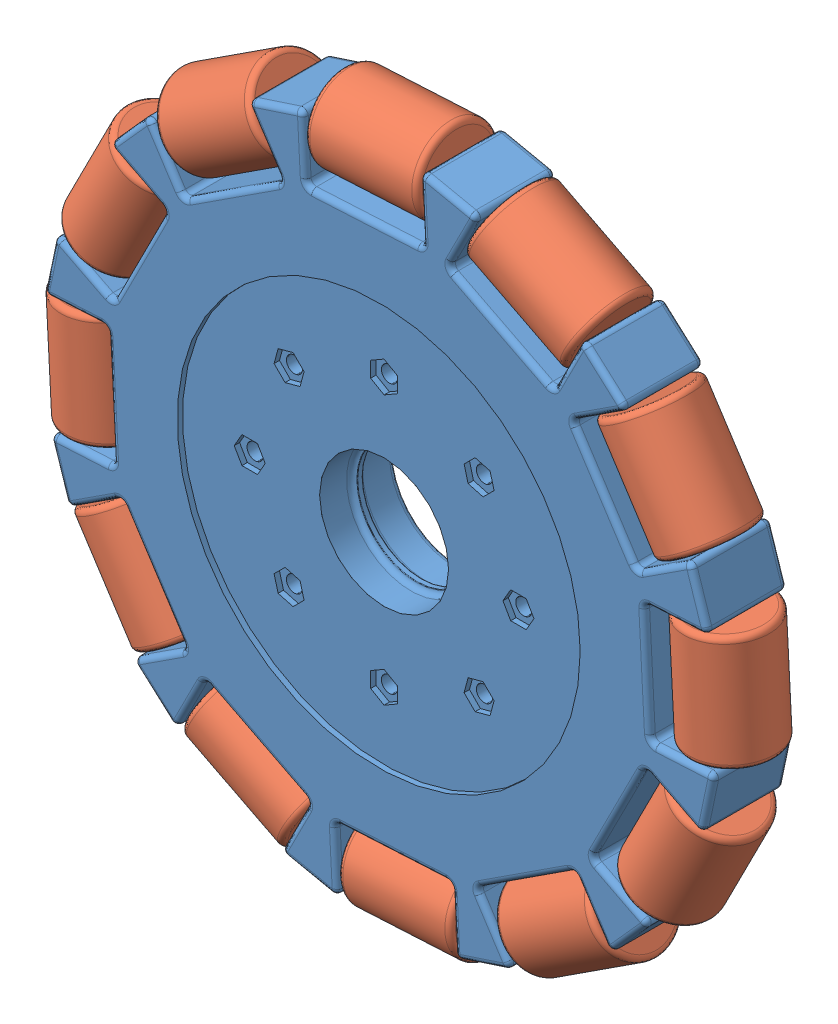
SolidWorks assembly single wheel assembly 1, configuration Default. Lengths in mm.
Overall size (138.11 135.78 21.9).
13 component instances, 2 part files, 24 mates.
Components (placement in the parent):
- basic-1: basic [Default] at (73.8485 -0.4973 -9.443) size (124.49 124.49 16)
- omni new-2: omni new [Default] at (131.2341 13.0674 -1.943) x (-0.527483 -0.02805 -0.849102) z (0.053103 -0.998589 0) size (15.5 15.5 21)
- omni new-3: omni new [Default] at (114.2887 -43.4123 -1.943) x (0.399732 -0.6145 -0.680151) z (-0.838252 -0.545283 0) size (15.5 15.5 21)
- omni new-4: omni new [Default] at (56.9031 -56.977 -1.943) x (0.429804 0.845142 0.31781) z (-0.891355 0.453306 0) size (15.5 15.5 21)
- omni new-5: omni new [Default] at (116.7635 39.9429 -1.943) x (-0.615632 -0.400469 0.678691) z (0.545283 -0.838252 0) size (15.5 15.5 21)
- omni new-6: omni new [Default] at (30.9334 -40.9374 -1.943) x (-0.31305 -0.203639 0.927648) z (-0.545283 0.838252 0) size (15.5 15.5 21)
- omni new-7: omni new [Default] at (130.3282 -17.4427 -1.943) x (0.582439 -0.296205 0.756986) z (-0.453306 -0.891355 0) size (15.5 15.5 21)
- omni new-8: omni new [Default] at (16.4629 -14.062 -1.943) x (0.884135 0.047016 -0.46486) z (-0.053103 0.998589 0) size (15.5 15.5 21)
- omni new-9: omni new [Default] at (87.4132 -57.8829 -1.943) x (-0.000877 0.016485 0.999864) z (-0.998589 -0.053103 0) size (15.5 15.5 21)
- omni new-10: omni new [Default] at (17.3687 16.4482 -1.943) x (-0.685244 0.348487 -0.639529) z (0.453306 0.891355 0) size (15.5 15.5 21)
- omni new-11: omni new [Default] at (60.2838 56.8883 -1.943) x (0.03476 -0.653654 0.755994) z (0.998589 0.053103 0) size (15.5 15.5 21)
- omni new-12: omni new [Default] at (33.4083 42.4178 -1.943) x (-0.043127 0.066299 0.996867) z (0.838252 0.545283 0) size (15.5 15.5 21)
- omni new-13: omni new [Default] at (90.7939 55.9825 -1.943) x (-0.379207 -0.745651 0.547911) z (0.891355 -0.453306 0) size (15.5 15.5 21)
Mates (geometry in assembly coordinates):
- Concentric1: concentric anti-aligned: cylinder of basic-1 through (52.3564 54.7435 -1.943) axis (-0.838252 -0.545283 0) radius 0.5; cylinder of omni new-12 through (7.674 25.6776 -1.943) axis (0.838252 0.545283 0) radius 0.505
- Concentric2: concentric anti-aligned: cylinder of basic-1 through (27.6154 36.5966 -1.943) axis (-0.453306 -0.891355 0) radius 0.5; cylinder of omni new-10 through (3.4522 -10.9164 -1.943) axis (0.453306 0.891355 0) radius 0.505
- Concentric4: concentric anti-aligned: cylinder of basic-1 through (15.2625 8.5104 -1.943) axis (0.053103 -0.998589 0) radius 0.5; cylinder of omni new-8 through (18.0931 -44.7187 -1.943) axis (-0.053103 0.998589 0) radius 0.505
- Concentric5: concentric anti-aligned: cylinder of basic-1 through (82.8562 58.0887 -1.943) axis (-0.998589 -0.053103 0) radius 0.5; cylinder of omni new-11 through (29.6271 55.2581 -1.943) axis (0.998589 0.053103 0) radius 0.505
- Concentric6: concentric anti-aligned: cylinder of basic-1 through (18.6077 -21.9893 -1.943) axis (0.545283 -0.838252 0) radius 0.5; cylinder of omni new-6 through (47.6736 -66.6718 -1.943) axis (-0.545283 0.838252 0) radius 0.505
- Concentric7: concentric anti-aligned: cylinder of basic-1 through (36.7546 -46.7303 -1.943) axis (0.891355 -0.453306 0) radius 0.5; cylinder of omni new-4 through (84.2676 -70.8935 -1.943) axis (-0.891355 0.453306 0) radius 0.505
- Concentric8: concentric anti-aligned: cylinder of basic-1 through (64.8408 -59.0832 -1.943) axis (0.998589 0.053103 0) radius 0.5; cylinder of omni new-9 through (118.0699 -56.2526 -1.943) axis (-0.998589 -0.053103 0) radius 0.505
- Concentric9: concentric anti-aligned: cylinder of basic-1 through (95.3406 -55.738 -1.943) axis (0.838252 0.545283 0) radius 0.5; cylinder of omni new-3 through (140.023 -26.6721 -1.943) axis (-0.838252 -0.545283 0) radius 0.505
- Concentric10: concentric anti-aligned: cylinder of basic-1 through (120.0816 -37.5912 -1.943) axis (0.453306 0.891355 0) radius 0.5; cylinder of omni new-7 through (144.2447 9.9219 -1.943) axis (-0.453306 -0.891355 0) radius 0.505
- Concentric11: concentric anti-aligned: cylinder of basic-1 through (132.4344 -9.505 -1.943) axis (-0.053103 0.998589 0) radius 0.5; cylinder of omni new-2 through (129.6038 43.7241 -1.943) axis (0.053103 -0.998589 0) radius 0.505
- Concentric12: concentric anti-aligned: cylinder of basic-1 through (129.0893 20.9948 -1.943) axis (-0.545283 0.838252 0) radius 0.5; cylinder of omni new-5 through (100.0233 65.6773 -1.943) axis (0.545283 -0.838252 0) radius 0.505
- Concentric13: concentric anti-aligned: cylinder of omni new-13 through (63.4293 69.899 -1.943) axis (0.891355 -0.453306 0) radius 0.505; cylinder of basic-1 through (110.9424 45.7358 -1.943) axis (-0.891355 0.453306 0) radius 0.5
- Width1: width anti-aligned: plane of omni new-12 through (51.0116 53.8687 -1.943) normal (0.838252 0.545283 0); plane of basic-1 through (33.4083 42.4178 -1.943) normal (-0.838252 -0.545283 0); plane of omni new-12 through (55.1739 48.1958 5.557) normal (-0.838252 -0.545283 0); plane of basic-1 through (36.9072 36.3133 5.557) normal (0.838252 0.545283 0)
- Width2: width anti-aligned: plane of omni new-10 through (26.8882 35.1666 -1.943) normal (0.453306 0.891355 0); plane of basic-1 through (17.3687 16.4482 -1.943) normal (-0.453306 -0.891355 0); plane of omni new-10 through (33.3293 32.3349 5.557) normal (-0.453306 -0.891355 0); plane of basic-1 through (23.4511 12.911 5.557) normal (0.453306 0.891355 0)
- Width3: width anti-aligned: plane of omni new-8 through (15.3477 6.9084 -1.943) normal (-0.053103 0.998589 0); plane of basic-1 through (16.4629 -14.062 -1.943) normal (0.053103 -0.998589 0); plane of omni new-8 through (22.3418 7.6766 5.557) normal (0.053103 -0.998589 0); plane of basic-1 through (23.4989 -14.0841 5.557) normal (-0.053103 0.998589 0)
- Width4: width anti-aligned: plane of omni new-6 through (19.4825 -23.3342 -1.943) normal (-0.545283 0.838252 0); plane of basic-1 through (30.9334 -40.9374 -1.943) normal (0.545283 -0.838252 0); plane of omni new-6 through (25.1554 -19.1719 5.557) normal (0.545283 -0.838252 0); plane of basic-1 through (37.0379 -37.4385 5.557) normal (-0.545283 0.838252 0)
- Width5: width anti-aligned: plane of omni new-4 through (38.1846 -47.4576 -1.943) normal (-0.891355 0.453306 0); plane of basic-1 through (56.9031 -56.977 -1.943) normal (0.891355 -0.453306 0); plane of omni new-4 through (41.0164 -41.0165 5.557) normal (0.891355 -0.453306 0); plane of basic-1 through (60.4402 -50.8946 5.557) normal (-0.891355 0.453306 0)
- Width6: width anti-aligned: plane of omni new-9 through (66.4428 -58.998 -1.943) normal (-0.998589 -0.053103 0); plane of basic-1 through (87.4132 -57.8829 -1.943) normal (0.998589 0.053103 0); plane of omni new-9 through (65.6746 -52.004 5.557) normal (0.998589 0.053103 0); plane of basic-1 through (87.4353 -50.8468 5.557) normal (-0.998589 -0.053103 0)
- Width7: width anti-aligned: plane of omni new-3 through (96.6854 -54.8632 -1.943) normal (-0.838252 -0.545283 0); plane of basic-1 through (114.2887 -43.4123 -1.943) normal (0.838252 0.545283 0); plane of omni new-3 through (92.5231 -49.1903 5.557) normal (0.838252 0.545283 0); plane of basic-1 through (110.7898 -37.3079 5.557) normal (-0.838252 -0.545283 0)
- Width8: width anti-aligned: plane of omni new-7 through (120.8088 -36.1611 -1.943) normal (-0.453306 -0.891355 0); plane of basic-1 through (130.3282 -17.4427 -1.943) normal (0.453306 0.891355 0); plane of omni new-7 through (114.3677 -33.3294 5.557) normal (0.453306 0.891355 0); plane of basic-1 through (124.2459 -13.9055 5.557) normal (-0.453306 -0.891355 0)
- Width9: width anti-aligned: plane of omni new-2 through (132.3492 -7.9029 -1.943) normal (0.053103 -0.998589 0); plane of basic-1 through (131.2341 13.0674 -1.943) normal (-0.053103 0.998589 0); plane of omni new-2 through (125.3552 -8.6711 5.557) normal (-0.053103 0.998589 0); plane of basic-1 through (124.198 13.0895 5.557) normal (0.053103 -0.998589 0)
- Width10: width anti-aligned: plane of omni new-5 through (128.2145 22.3396 -1.943) normal (0.545283 -0.838252 0); plane of basic-1 through (116.7635 39.9429 -1.943) normal (-0.545283 0.838252 0); plane of omni new-5 through (122.5415 18.1773 5.557) normal (-0.545283 0.838252 0); plane of basic-1 through (110.6591 36.444 5.557) normal (0.545283 -0.838252 0)
- Width11: width anti-aligned: plane of omni new-13 through (109.5124 46.463 -1.943) normal (0.891355 -0.453306 0); plane of basic-1 through (90.7939 55.9825 -1.943) normal (-0.891355 0.453306 0); plane of omni new-13 through (106.6806 40.0219 5.557) normal (-0.891355 0.453306 0); plane of basic-1 through (87.2567 49.9001 5.557) normal (0.891355 -0.453306 0)
- Width12: width anti-aligned: plane of omni new-11 through (60.2838 56.8883 -1.943) normal (-0.998589 -0.053103 0); plane of basic-1 through (81.2542 58.0035 -1.943) normal (0.998589 0.053103 0); plane of omni new-11 through (60.2617 49.8523 5.557) normal (0.998589 0.053103 0); plane of basic-1 through (82.0223 51.0095 5.557) normal (-0.998589 -0.053103 0)
